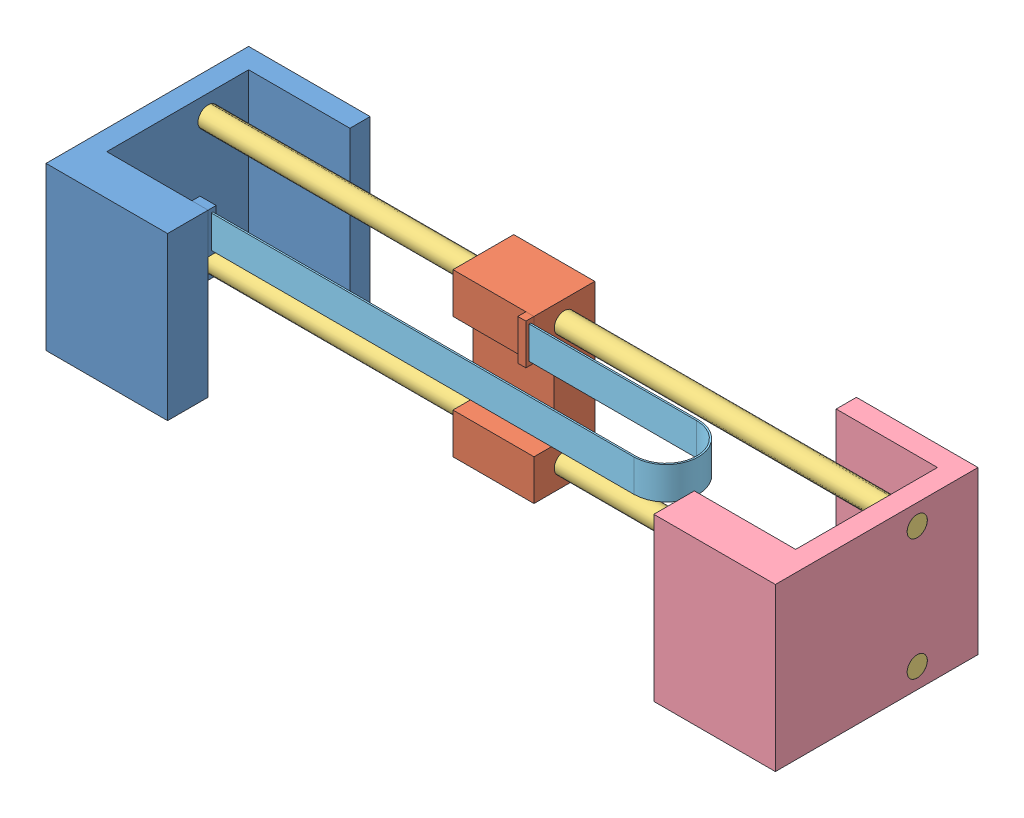
SolidWorks assembly 01_FLEX CABLE ASSEMBLY, configuration Default. Lengths in mm.
Overall size (900 200 250).
6 component instances, 5 part files, 14 mates.
Components (placement in the parent):
- 02_BASE STRUCTURE-1: 02_BASE STRUCTURE [Default] at (7.5916 -98.3496 159.4493) size (150 200 250)
- 04_SLIDER-1: 04_SLIDER [Default] at (222.2227 101.6504 21.9493) x (0 -1 0) z (0 0 1) size (200 100 85)
- 03_GUIDE WAY-1: 03_GUIDE WAY [Default] at (-142.4084 -73.3496 -15.5507) size (900 25 25)
- 01_BASE STRUCTURE-3: 01_BASE STRUCTURE [Default] at (607.5916 101.6504 159.4493) x (-1 0 0) z (0 0 1) size (150 200 250)
- 03_GUIDE WAY-2: 03_GUIDE WAY [Default] at (-142.4084 76.6504 -15.5507) size (900 25 25)
- 05_FLEX CABLE-1: 05_FLEX CABLE [Default] at (7.5916 101.6504 159.4493) x (1 0 0) z (0 1 0) size (561.2 79.5 40)
Mates (geometry in assembly coordinates):
- Coincident2: coincident aligned: plane of resting-piller-pt-01-1 through (7.5916 101.6504 -90.5507) normal (0 0 -1); plane of resting-piller-pt-01-2 through (607.5916 -98.3496 -90.5507) normal (0 0 -1)
- Coincident3: coincident aligned: plane of resting-piller-pt-01-1 through (7.5916 -98.3496 159.4493) normal (0 -1 0); plane of resting-piller-pt-01-2 through (607.5916 -98.3496 159.4493) normal (0 -1 0)
- Concentric1: concentric anti-aligned: cylinder of resting-piller-pt-01-1 through (-142.4084 -73.3496 -15.5507) axis (-1 0 0) radius 12.5; cylinder of guide-piller-pt-02-1 through (-142.4084 -73.3496 -15.5507) axis (1 0 0) radius 12.5
- Concentric2: concentric anti-aligned: cylinder of resting-piller-pt-01-1 through (-142.4084 76.6504 -15.5507) axis (-1 0 0) radius 12.5; cylinder of guide-piller-pt-02-2 through (-142.4084 76.6504 -15.5507) axis (1 0 0) radius 12.5
- Coincident4: coincident aligned: plane of resting-piller-pt-01-1 through (-142.4084 101.6504 159.4493) normal (-1 0 0); plane of guide-piller-pt-02-1 through (-142.4084 -73.3496 -15.5507) normal (-1 0 0)
- Coincident5: coincident aligned: plane of resting-piller-pt-01-1 through (-142.4084 101.6504 159.4493) normal (-1 0 0); plane of guide-piller-pt-02-2 through (-142.4084 76.6504 -15.5507) normal (-1 0 0)
- Concentric5: concentric anti-aligned: cylinder of guide-piller-pt-03-1 through (222.2227 -73.3496 -15.5507) axis (-1 0 0) radius 12.5; cylinder of guide-piller-pt-02-1 through (-142.4084 -73.3496 -15.5507) axis (1 0 0) radius 12.5
- Concentric6: concentric anti-aligned: cylinder of guide-piller-pt-03-1 through (222.2227 76.6504 -15.5507) axis (-1 0 0) radius 12.5; cylinder of guide-piller-pt-02-2 through (-142.4084 76.6504 -15.5507) axis (1 0 0) radius 12.5
- LimitDistance2: limit distance = 339.6312 mm anti-aligned: plane of resting-piller-pt-01-1 through (-117.4084 101.6504 109.4493) normal (1 0 0); plane of guide-piller-pt-03-1 through (222.2227 101.6504 21.9493) normal (-1 0 0)
- Coincident8: coincident aligned: plane of resting-piller-pt-01-2 through (757.5916 -98.3496 159.4493) normal (1 0 0); plane of guide-piller-pt-02-2 through (757.5916 76.6504 -15.5507) normal (1 0 0)
- InPlace1: in place: plane of 02_BASE STRUCTURE-1 through (7.5916 101.6504 99.4493) normal (0 1 0); plane of ? through (0 101.6504 0) normal (0 1 0); moOrthogonalPlaneRef_w of 02_BASE STRUCTURE-1 through (7.5916 101.6504 99.4493) normal (0 1 0); plane of ? through (0 101.6504 0) normal (0 0 -1); plane of 02_BASE STRUCTURE-1 through (7.5916 101.6504 99.4493) normal (0 1 0); plane of ? through (0 101.6504 0) normal (1 0 0); plane of 02_BASE STRUCTURE-1 through (7.5916 101.6504 99.4493) normal (0 1 0); unknown of 05_FLEX CABLE-1
- Coincident9: coincident aligned: plane of ?; plane of ?
- Coincident10: coincident aligned: moOrthogonalPlaneRef_w of 02_BASE STRUCTURE-1 through (7.5916 101.6504 159.4493) normal (0 0 -1); plane of Part1^01_FLEX CABLE ASSEMBLY-1 through (7.5916 101.6504 159.4493) normal (0 0 -1)
- Coincident11: coincident anti-aligned: moOrthogonalPlaneRef_w of 02_BASE STRUCTURE-1 through (7.5916 101.6504 159.4493) normal (-1 0 0); plane of Part1^01_FLEX CABLE ASSEMBLY-1 through (7.5916 101.6504 159.4493) normal (1 0 0)
